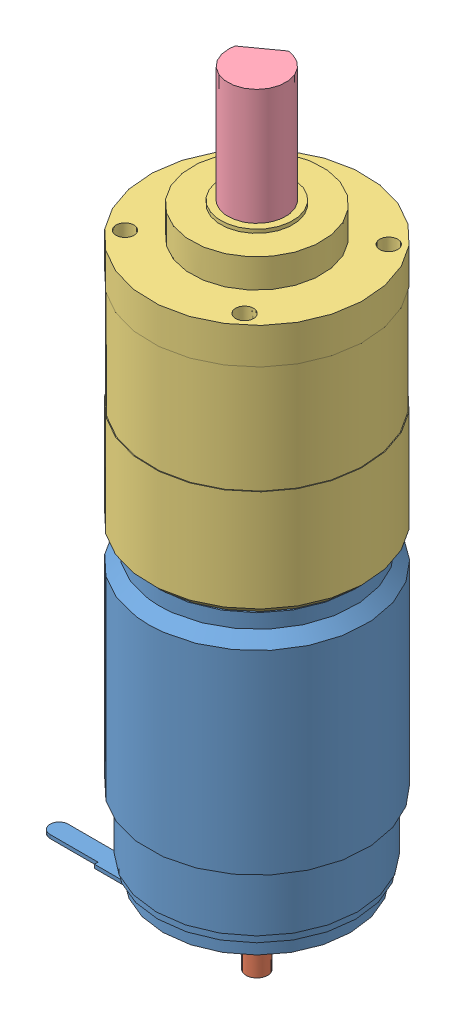
SolidWorks assembly Motoreducteur_Faulhauber_3042W024_30_1, configuration Default. Lengths in mm.
Overall size (42.24 108.6 42.24).
4 component instances, 4 part files, 8 mates.
Components (placement in the parent):
- corps_moteur_faulhauber_3042W024C-1: corps_moteur_faulhauber_3042W024C [Default] at (-5.2131 -12.6529 -1.1935) size (35.9 47.3 30)
- arbre_moteur_faulhauber_3042W024C-1: arbre_moteur_faulhauber_3042W024C [Default] at (-5.2131 41.7471 -1.1935) x (0 -1 0) z (-0.776717 0 -0.629849) size (65.3 4 4)
- corps_reducteur_faulhaber_30_1-1: corps_reducteur_faulhaber_30_1 [Default] at (-5.2131 64.4471 -1.1935) x (0.769654 0 -0.638462) z (0 -1 0) size (30 30 39.6)
- arbre_reducteur_faulhauber_30_1-1: arbre_reducteur_faulhauber_30_1 [Default] at (-5.2131 64.4471 -1.1935) x (0.811588 0 -0.584231) z (0.584231 0 0.811588) size (8 20.6 8)
Mates (geometry in assembly coordinates):
- Coaxiale1: concentric aligned: cylinder of corps_moteur_faulhauber_3042W024C-1; cylinder of arbre_moteur_faulhauber_3042W024C-1
- Coïncidente1: coincident anti-aligned: plane of corps_moteur_faulhauber_3042W024C-1 through (-5.2131 21.7471 -1.1935) normal (0 1 0); plane of arbre_moteur_faulhauber_3042W024C-1 through (-5.2131 21.7471 -1.1935) normal (0 -1 0)
- Coaxiale3: concentric aligned: cylinder of corps_moteur_faulhauber_3042W024C-1; cylinder of corps_reducteur_faulhaber_30_1-1
- Coïncidente2: coincident anti-aligned: plane of corps_moteur_faulhauber_3042W024C-1 through (-5.2131 29.3471 -1.1935) normal (0 1 0); plane of corps_reducteur_faulhaber_30_1-1 through (-5.2131 29.3471 -1.1935) normal (0 -1 0)
- Tangent1: tangent aligned: plane of corps_moteur_faulhauber_3042W024C-1 through (-18.2131 -13.1529 8.3565) normal (0 0 1); cylinder of corps_reducteur_faulhaber_30_1-1
- Coaxiale4: concentric aligned: cylinder of corps_reducteur_faulhaber_30_1-1; cylinder of arbre_reducteur_faulhauber_30_1-1
- Coïncidente3: coincident anti-aligned: plane of corps_reducteur_faulhaber_30_1-1 through (-5.2131 64.4471 -1.1935) normal (0 1 0); plane of arbre_reducteur_faulhauber_30_1-1 through (-5.2131 64.4471 -1.1935) normal (0 -1 0)
- Contr.Engrenages1: gear = 0.001 : 0.024: cylinder of arbre_reducteur_faulhauber_30_1-1; cylinder of arbre_moteur_faulhauber_3042W024C-1
